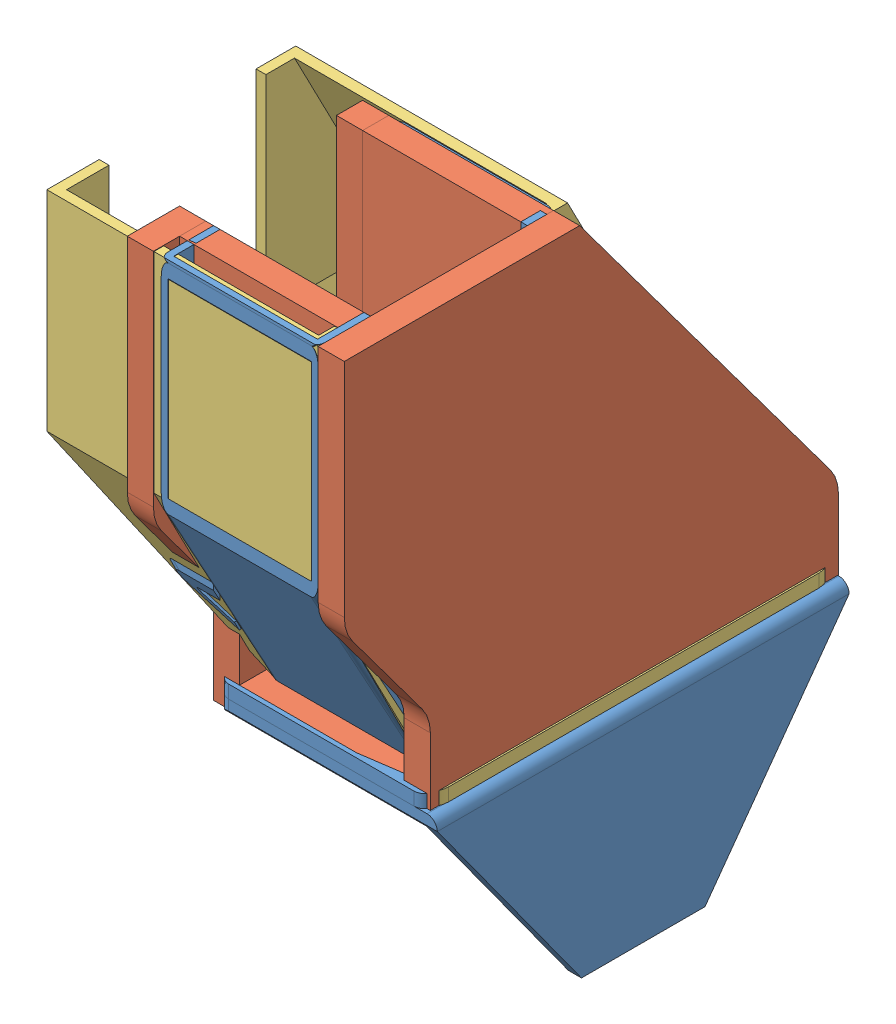
SolidWorks assembly gantry risers, configuration Default. Lengths in mm.
Overall size (150.25 311.14 239.5).
3 component instances, 3 part files, 5 mates.
Components (placement in the parent):
- steel risers-1: steel risers [Default] at (-36.2 0 0) size (169.12 311.36 239.64)
- gantry risers-1: gantry risers [left] at origin size (105.4 216.11 240) (hidden)
- steel plate gantry risers-1: steel plate gantry risers [Default] at origin size (145.5 209.55 239.5)
Mates (geometry in assembly coordinates):
- Coincident2: coordinate: point of gantry risers-1
- Coincident3: coincident aligned: plane of steel risers-1 through (40 119.405 214.6) normal (0 0 -1); plane of gantry risers-1 through (-223.7 216.11 214.6) normal (0 0 -1)
- Coincident4: coincident aligned: plane of steel risers-1 through (40 114.405 143.4) normal (0 1 0); plane of gantry risers-1 through (-223.7 114.405 209.6) normal (0 1 0)
- Coincident5: coincident anti-aligned: plane of steel risers-1 through (40 257.9917 259.6981) normal (1 0 0); plane of gantry risers-1 through (40 0 0) normal (-1 0 0)
- Coincident6: coordinate: unknown of steel plate gantry risers-1
